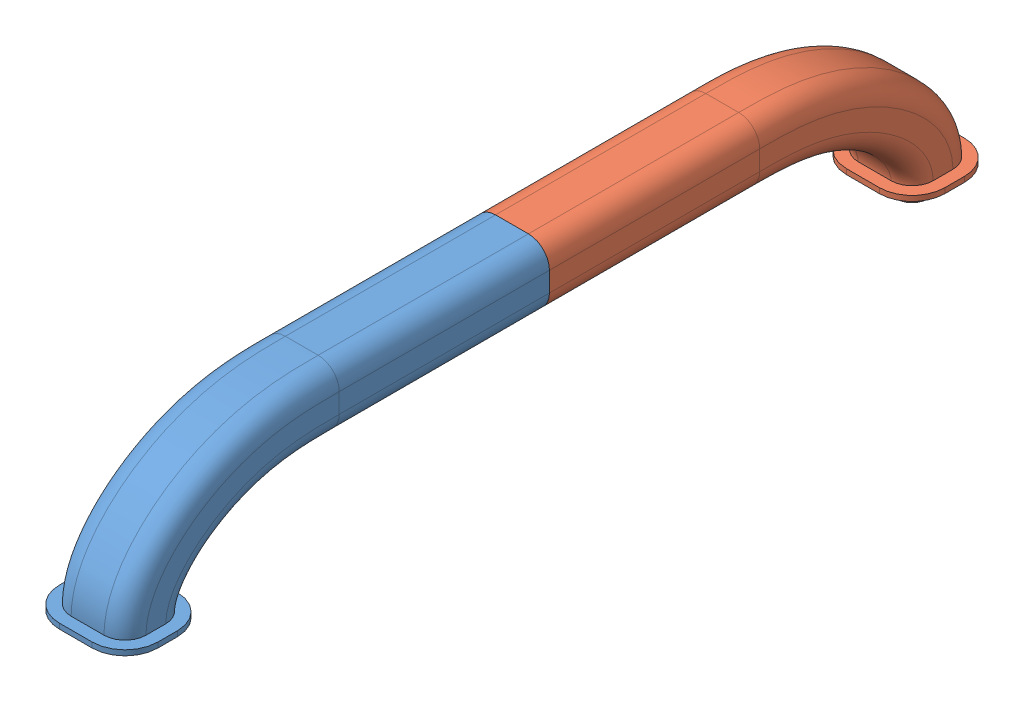
SolidWorks assembly Assemblage_support, configuration Défaut. Lengths in mm.
Overall size (75 117.02 664.04).
2 component instances, 2 part files, 3 mates.
Components (placement in the parent):
- support_numero2-1: support_numero2 [Défaut] at (141.9181 50.18 169.7744) size (75 117.02 352.02)
- support_numero1-1: support_numero1 [Défaut] at (142.6897 50.18 169.7744) x (-1 0 0) z (0 0 -1) size (75 117.02 332.02)
Mates (geometry in assembly coordinates):
- Coïncidente1: coincident anti-aligned: plane of support_numero2-1 through (164.8039 57.1977 189.7744) normal (1 0 0); plane of support_numero1-1 through (164.8039 42.1977 169.7744) normal (-1 0 0)
- Coïncidente2: coincident anti-aligned: plane of support_numero2-1 through (154.8039 67.1977 189.7744) normal (0 1 0); plane of support_numero1-1 through (154.8039 67.1977 169.7744) normal (0 -1 0)
- Coïncidente3: coincident anti-aligned: plane of support_numero2-1 through (129.8039 57.1977 169.7744) normal (0 0 -1); plane of support_numero1-1 through (154.8039 57.1977 169.7744) normal (0 0 1)
